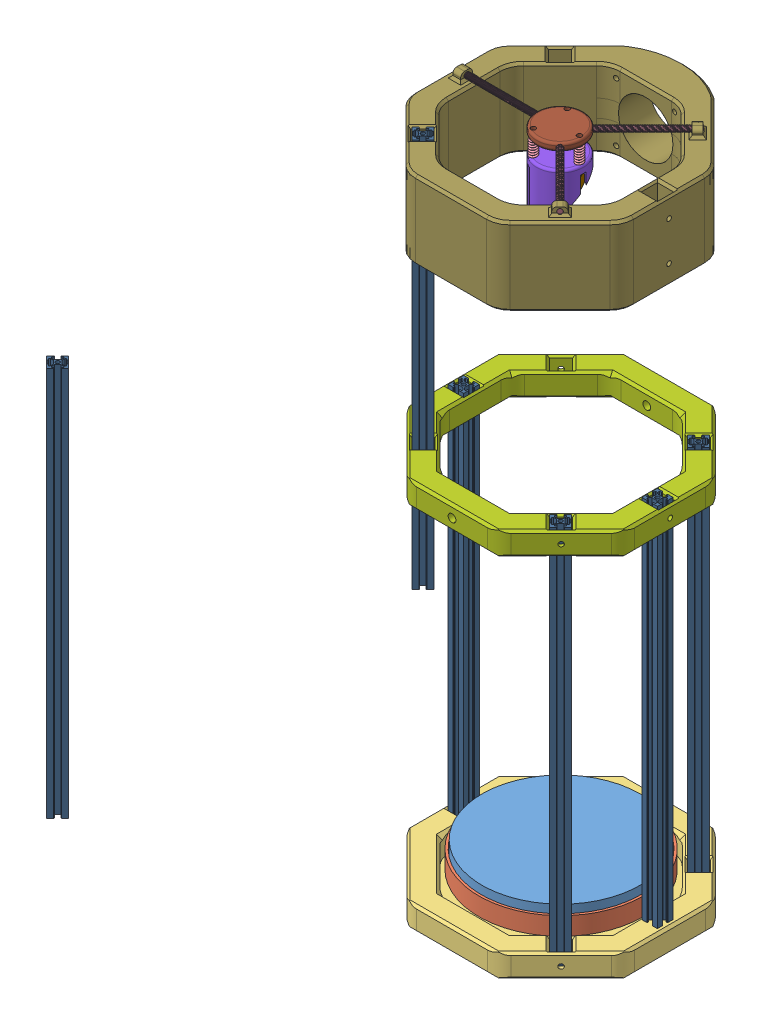
SolidWorks assembly telescope, configuration Default. Lengths in mm.
Overall size (446.79 865.74 529.28).
35 component instances, 13 part files, 75 mates.
Components (placement in the parent):
- primary_mirror-1: primary_mirror [Default] at origin size (203.2 25 203.2)
- primary_mirror_mount-1: primary_mirror_mount [Default] at (0 -5 0) x (0.5 0 -0.866025) z (0.866025 0 0.5) size (211 23 211)
- bottom_ring-1: bottom_ring [Default] at (0 -32 0) x (0 0 -1) z (1 0 0) size (280 30 280)
- spring-4: spring [Default] at (60.6218 -28 -35) size (10.35 22 11.55) (flexible)
  - spring-1: spring [Default] at origin size (10.35 22 11.55)
- spring-5: spring [Default] at (0 -28 70) size (10.35 22 11.55) (flexible)
  - spring-1: spring [Default] at origin size (10.35 22 11.55)
- spring-6: spring [Default] at (-60.6218 -28 -35) size (10.35 22 11.55) (flexible)
  - spring-1: spring [Default] at origin size (10.35 22 11.55)
- hexalobular socket cheese head_iso-8: hexalobular socket cheese head_iso [ISO 14580 - #6 x 40 x 38 - 4.8-N] at (-60.6218 -45 -35) size (10 44.4 10)
- hexalobular socket cheese head_iso-9: hexalobular socket cheese head_iso [ISO 14580 - #6 x 40 x 38 - 4.8-N] at (60.6218 -45 -35) size (10 44.4 10)
- hexalobular socket cheese head_iso-10: hexalobular socket cheese head_iso [ISO 14580 - #6 x 40 x 38 - 4.8-N] at (0 -45 70) size (10 44.4 10)
- hex nut gradec_iso-5: hex nut gradec_iso [ISO - 4034 - M6 - N] at (60.6218 -38.1 -35) x (1 0 0) z (0 -1 0) size (10 11.55 6.1)
- hex nut gradec_iso-6: hex nut gradec_iso [ISO - 4034 - M6 - N] at (-60.6218 -38.1 -35) x (1 0 0) z (0 -1 0) size (10 11.55 6.1)
- hex nut gradec_iso-7: hex nut gradec_iso [ISO - 4034 - M6 - N] at (0 -38.1 70) x (0.980222 0 -0.197901) z (0 -1 0) size (10 11.55 6.1)
- middle_ring-1: middle_ring [Default] at (0 437.3298 0) x (0 0 1) z (-1 0 0) size (280 30 280)
- secondary_mirror_mount-2: secondary_mirror_mount [Default] at (-0.7071 790.2811 0.7071) x (-0.5 0 0.866025) z (0.866025 0 0.5) size (60 72.96 60)
- secondary_mirror-2: secondary_mirror [Default] at (-1.1853 758.4823 0.5609) x (-0.353553 -0.707107 0.612372) z (-0.353553 0.707107 0.612372) size (80.71 50 10)
- spring-12: spring [Default] at (-13.2071 790.2811 22.3577) size (10.35 22 11.55)
  - spring-1: spring [Default] at origin size (10.35 22 11.55)
- spring-13: spring [Default] at (-13.2071 790.2811 -20.9435) size (10.35 22 11.55)
  - spring-1: spring [Default] at origin size (10.35 22 11.55)
- spring-14: spring [Default] at (24.2929 790.2811 0.7071) size (10.35 22 11.55)
  - spring-1: spring [Default] at origin size (10.35 22 11.55)
- aluminum_extrusion-1: aluminum_extrusion [Default] at (88.3883 -32 89.0955) x (0.707107 0 0.707107) z (-0.707107 0 0.707107) size (20 500 20)
- aluminum_extrusion-2: aluminum_extrusion [Default] at (-125.5 -32 -0.5) x (-1 0 0) z (0 0 -1) size (20 500 20)
- aluminum_extrusion-3: aluminum_extrusion [Default] at (88.3883 -32 -87.6812) x (-0.707107 0 0.707107) z (-0.707107 0 -0.707107) size (20 500 20)
- secondary_mirror_mount_2-1: secondary_mirror_mount_2 [Default] at (-0.7071 810.2811 0.7071) x (0 0 1) z (-1 0 0) size (60 10.36 60.12)
- upper_ring_focuser-2: upper_ring_focuser [Default] at (-0.7071 710.2811 0.7071) x (-1 0 0) z (0 0 -1) size (280 110 298.17)
- aluminum_extrusion-4: aluminum_extrusion [Default] at (-88.3883 310.2811 89.0955) x (0.707107 0 0.707107) z (-0.707107 0 0.707107) size (20 500 20)
- Threaded Rod-2: Threaded Rod [90mm, 6mm] at (13.435 815.2811 -13.435) x (0.5 0.707107 0.5) z (0.5 -0.707107 0.5) size (7.18 110.79 8.28)
- Threaded Rod-3: Threaded Rod [90mm, 6mm] at (91.2168 815.2811 92.631) x (-0.706924 0.022716 0.706924) z (0.016062 0.999742 -0.016062) size (7.18 110.79 8.28)
- Threaded Rod-4: Threaded Rod [90mm, 6mm] at (-130.7071 815.2811 0.7071) x (0 -0.381849 0.924225) z (0 -0.924225 -0.381849) size (7.18 110.79 8.28)
- aluminum_extrusion-5: aluminum_extrusion [Default] at (-288.5277 90.2535 357.666) x (0.707107 0 0.707107) z (-0.707107 0 0.707107) size (20 500 20)
- aluminum_extrusion-6: aluminum_extrusion [Default] at (123.7929 467.4029 0.2071) x (-1 0 0) z (0 0 1) size (20 500 20)
Mates (geometry in assembly coordinates):
- Concentric1: concentric aligned: cylinder of primary_mirror-1 through (0 25 0) axis (0 -1 0) radius 101.6; cylinder of primary_mirror_mount-1 through (0 15 0) axis (0 -1 0) radius 102.5
- Coincident2: coordinate: point of primary_mirror-1
- Parallel1: parallel anti-aligned: plane of primary_mirror-1 through (0 25 0) normal (0 1 0); plane of middle_ring-1 through (0 437.3298 0) normal (0 -1 0)
- Coincident4: coincident aligned: line of middle_ring-1 through (0 468.8298 0) axis (0 -1 0)
- Parallel2: parallel anti-aligned: plane of middle_ring-1 through (-140 467.3298 -57.9899) normal (-1 0 0)
- Coincident6: coincident aligned: line of bottom_ring-1 through (33 0 -0.5) axis (0 0 -1)
- Parallel3: parallel anti-aligned: plane of middle_ring-1 through (-57.9899 467.3298 140) normal (0 0 1); plane of bottom_ring-1 through (57.9899 -2 -140) normal (0 0 -1)
- Concentric2: concentric anti-aligned: cylinder of primary_mirror_mount-1 through (-60.6218 0 -35) axis (0 -1 0) radius 6.5; cylinder of bottom_ring-1 through (-60.6218 -32 -35) axis (0 1 0) radius 3
- Concentric6: concentric: cylinder of bottom_ring-1 through (60.6218 -32 -35) axis (0 1 0) radius 3; point of spring-4
- Concentric7: concentric: cylinder of bottom_ring-1 through (0 -32 70) axis (0 1 0) radius 3; point of spring-5
- Concentric8: concentric: cylinder of bottom_ring-1 through (-60.6218 -32 -35) axis (0 1 0) radius 3; point of spring-6
- Coincident24: coincident anti-aligned: plane of bottom_ring-1 through (0 -28 0) normal (0 1 0); plane of spring-5/spring-1 through (0 -28 70) normal (0 -1 0)
- Coincident25: coincident anti-aligned: plane of bottom_ring-1 through (0 -28 0) normal (0 1 0); plane of spring-4/spring-1 through (60.6218 -28 -35) normal (0 -1 0)
- Coincident26: coincident anti-aligned: plane of bottom_ring-1 through (0 -28 0) normal (0 1 0); plane of spring-6/spring-1 through (-60.6218 -28 -35) normal (0 -1 0)
- Parallel6: parallel aligned: plane of spring-4 through (60.6218 -28 -35) normal (0 0 1)
- Parallel7: parallel aligned: plane of spring-5 through (0 -28 70) normal (0 0 1)
- Parallel8: parallel aligned: plane of spring-6 through (-60.6218 -28 -35) normal (0 0 1)
- Coincident32: coincident anti-aligned: plane of primary_mirror_mount-1 through (0 -8 0) normal (0 -1 0); plane of spring-6/spring-1 through (-60.6218 -8 -35) normal (0 1 0)
- Concentric13: concentric aligned: cylinder of primary_mirror_mount-1 through (-60.6218 0 -35) axis (0 -1 0) radius 6.5; cylinder of hexalobular socket cheese head_iso-8 through (-60.6218 -45 -35) axis (0 -1 0) radius 3.4
- Coincident36: coincident anti-aligned: plane of primary_mirror_mount-1 through (0 -5 0) normal (0 1 0); plane of hexalobular socket cheese head_iso-8 through (-57.6218 -5 -35) normal (0 -1 0)
- Concentric14: concentric anti-aligned: cylinder of primary_mirror_mount-1 through (60.6218 -8 -35) axis (0 1 0) radius 3; cylinder of hexalobular socket cheese head_iso-9 through (60.6218 -45 -35) axis (0 -1 0) radius 3.4
- Coincident37: coincident anti-aligned: plane of primary_mirror_mount-1 through (0 -5 0) normal (0 1 0); plane of hexalobular socket cheese head_iso-9 through (63.6218 -5 -35) normal (0 -1 0)
- Concentric15: concentric anti-aligned: cylinder of primary_mirror_mount-1 through (0 -8 70) axis (0 1 0) radius 3; cylinder of hexalobular socket cheese head_iso-10 through (0 -45 70) axis (0 -1 0) radius 3.4
- Coincident38: coincident anti-aligned: plane of primary_mirror_mount-1 through (0 -5 0) normal (0 1 0); plane of hexalobular socket cheese head_iso-10 through (3 -5 70) normal (0 -1 0)
- Coincident40: coincident anti-aligned: plane of primary_mirror-1 through (0 0 0) normal (0 -1 0); plane of primary_mirror_mount-1 through (0 0 0) normal (0 1 0)
- Concentric19: concentric aligned: cylinder of hexalobular socket cheese head_iso-9 through (60.6218 -45 -35) axis (0 -1 0) radius 3.4; cylinder of hex nut gradec_iso-5 through (60.6218 -13.0625 -35) axis (0 -1 0) radius 3
- Coincident41: coincident anti-aligned: plane of bottom_ring-1 through (0 -32 0) normal (0 -1 0); plane of hex nut gradec_iso-5 through (50.6218 -32 -35) normal (0 1 0)
- Concentric20: concentric aligned: cylinder of hexalobular socket cheese head_iso-8 through (-60.6218 -45 -35) axis (0 -1 0) radius 3.4; cylinder of hex nut gradec_iso-6 through (-60.6218 -13.0625 -35) axis (0 -1 0) radius 3
- Coincident42: coincident anti-aligned: plane of bottom_ring-1 through (0 -32 0) normal (0 -1 0); plane of hex nut gradec_iso-6 through (-70.6218 -32 -35) normal (0 1 0)
- Concentric21: concentric aligned: cylinder of hexalobular socket cheese head_iso-10 through (0 -45 70) axis (0 -1 0) radius 3.4; cylinder of hex nut gradec_iso-7 through (0 -13.0625 70) axis (0 -1 0) radius 3
- Coincident43: coincident anti-aligned: plane of bottom_ring-1 through (0 -32 0) normal (0 -1 0); plane of hex nut gradec_iso-7 through (-9.8022 -32 71.979) normal (0 1 0)
- Coincident45: coincident anti-aligned: plane of secondary_mirror_mount-2 through (7.2145 774.4379 -13.0135) normal (0.353553 -0.707107 -0.612372); plane of secondary_mirror-2 through (-1.1853 758.4823 0.5609) normal (-0.353553 0.707107 0.612372)
- Parallel12: parallel: cylinder of assembly; face of secondary_mirror_mount-2; cylinder of secondary_mirror-2 through (-1.1853 793.8377 0.5609) axis (0 -1 0) radius 25
- Parallel13: parallel: cylinder of assembly; face of secondary_mirror_mount-2; cylinder of secondary_mirror-2 through (-1.1853 793.8377 0.5609) axis (0 -1 0) radius 25
- Tangent3: tangent: cylinder of assembly; face of secondary_mirror_mount-2; cylinder of secondary_mirror-2 through (-1.1853 793.8377 0.5609) axis (0 -1 0) radius 25
- Parallel15: parallel aligned: plane of secondary_mirror_mount-2 through (-0.7071 790.2811 0.7071) normal (0 1 0)
- Coincident51: coincident anti-aligned: plane of secondary_mirror_mount-2 through (-0.7071 790.2811 0.7071) normal (0 1 0); plane of spring-12/spring-1 through (-13.2071 790.2811 22.3577) normal (0 -1 0)
- Concentric22: concentric: cylinder of secondary_mirror_mount-2 through (-13.2071 790.2811 22.3577) axis (0 -1 0) radius 3; point of spring-12
- Coincident53: coincident anti-aligned: plane of secondary_mirror_mount-2 through (-0.7071 790.2811 0.7071) normal (0 1 0); plane of spring-13/spring-1 through (-13.2071 790.2811 -20.9435) normal (0 -1 0)
- Concentric23: concentric: cylinder of secondary_mirror_mount-2 through (-13.2071 790.2811 -20.9435) axis (0 -1 0) radius 3; point of spring-13
- Coincident55: coincident anti-aligned: plane of secondary_mirror_mount-2 through (-0.7071 790.2811 0.7071) normal (0 1 0); plane of spring-14/spring-1 through (24.2929 790.2811 0.7071) normal (0 -1 0)
- Concentric24: concentric: cylinder of secondary_mirror_mount-2 through (24.2929 790.2811 0.7071) axis (0 -1 0) radius 3; point of spring-14
- LimitDistance1: limit distance = 733.4823 mm: plane of primary_mirror-1 through (0 25 0) normal (0 1 0); point of secondary_mirror-2
- Coincident62: coincident aligned: plane of bottom_ring-1 through (0 -32 0) normal (0 -1 0); plane of aluminum_extrusion-1 through (88.3883 -32 89.0955) normal (0 -1 0)
- Coincident63: coincident anti-aligned: plane of bottom_ring-1 through (88.3883 -2 103.2376) normal (0.707107 0 -0.707107); plane of aluminum_extrusion-1 through (81.3173 468 96.1665) normal (-0.707107 0 0.707107)
- Coincident65: coincident anti-aligned: plane of bottom_ring-1 through (103.2376 -2 88.3883) normal (-0.707107 0 -0.707107); plane of aluminum_extrusion-1 through (95.4594 468 96.1665) normal (0.707107 0 0.707107)
- Coincident66: coincident aligned: plane of bottom_ring-1 through (0 -32 0) normal (0 -1 0); plane of aluminum_extrusion-3 through (88.3883 -32 -87.6812) normal (0 -1 0)
- Coincident67: coincident aligned: plane of bottom_ring-1 through (0 -32 0) normal (0 -1 0); plane of aluminum_extrusion-2 through (-125.5 -32 -0.5) normal (0 -1 0)
- Coincident68: coincident anti-aligned: plane of bottom_ring-1 through (-135.5 -2 10.5) normal (1 0 0); plane of aluminum_extrusion-2 through (-135.5 468 -0.5) normal (-1 0 0)
- Coincident69: coincident anti-aligned: plane of bottom_ring-1 through (-135.5 -2 -10.5) normal (0 0 1); plane of aluminum_extrusion-2 through (-125.5 468 -10.5) normal (0 0 -1)
- Coincident70: coincident anti-aligned: plane of bottom_ring-1 through (73.5391 -2 -88.3883) normal (0.707107 0 -0.707107); plane of aluminum_extrusion-3 through (81.3173 468 -80.6102) normal (-0.707107 0 0.707107)
- Coincident71: coincident anti-aligned: plane of bottom_ring-1 through (103.2376 -2 -88.3883) normal (-0.707107 0 -0.707107); plane of aluminum_extrusion-3 through (95.4594 468 -80.6102) normal (0.707107 0 0.707107)
- Coincident72: coincident anti-aligned: plane of spring-12/spring-1 through (-13.2071 810.2811 22.3577) normal (0 1 0); plane of secondary_mirror_mount_2-1 through (-0.7071 810.2811 0.7071) normal (0 -1 0)
- Concentric25: concentric: point of spring-14; cylinder of secondary_mirror_mount_2-1 through (24.2929 820.2811 0.7071) axis (0 -1 0) radius 3
- Concentric26: concentric: point of spring-13; cylinder of secondary_mirror_mount_2-1 through (-13.2071 820.2811 -20.9435) axis (0 -1 0) radius 3
- LimitDistance2: limit distance = 0.6702 mm aligned: plane of middle_ring-1 through (0 467.3298 0) normal (0 1 0); plane of aluminum_extrusion-1 through (88.3883 468 89.0955) normal (0 1 0)
- Coincident78: coincident anti-aligned: plane of middle_ring-1 through (-88.3883 467.3298 103.2376) normal (0.707107 0 -0.707107); plane of aluminum_extrusion-4 through (-95.4594 810.2811 96.1665) normal (-0.707107 0 0.707107)
- Coincident79: coincident anti-aligned: plane of middle_ring-1 through (-88.3883 467.3298 103.2376) normal (-0.707107 0 -0.707107); plane of aluminum_extrusion-4 through (-81.3173 810.2811 96.1665) normal (0.707107 0 0.707107)
- LimitDistance4: limit distance = 127.0487 mm aligned: plane of middle_ring-1 through (0 437.3298 0) normal (0 -1 0); plane of aluminum_extrusion-4 through (-88.3883 310.2811 89.0955) normal (0 -1 0)
- Concentric27: concentric aligned: cylinder of secondary_mirror_mount_2-1 through (-30.7071 815.2811 0.7071) axis (1 0 0) radius 3; cylinder of upper_ring_focuser-2 through (-130.7071 815.2811 0.7071) axis (1 0 0) radius 3
- Parallel16: parallel aligned: plane of middle_ring-1 through (0 467.3298 0) normal (0 1 0); plane of aluminum_extrusion-1 through (88.3883 468 89.0955) normal (0 1 0)
- Concentric28: concentric aligned: cylinder of secondary_mirror_mount_2-1 through (29.2929 815.2811 -29.2929) axis (-0.707107 0 0.707107) radius 3; cylinder of upper_ring_focuser-2 through (91.2168 815.2811 -91.2168) axis (-0.707107 0 0.707107) radius 3
- Coincident85: coincident anti-aligned: plane of upper_ring_focuser-2 through (6.7175 810.2811 8.1317) normal (-0.707107 0 -0.707107); plane of aluminum_extrusion-4 through (-81.3173 810.2811 96.1665) normal (0.707107 0 0.707107)
- Coincident86: coincident anti-aligned: plane of upper_ring_focuser-2 through (-81.6708 810.2811 81.6708) normal (-0.707107 0 0.707107); plane of aluminum_extrusion-4 through (-81.3173 810.2811 82.0244) normal (0.707107 0 -0.707107)
- LimitDistance5: limit distance = 332.2811 mm anti-aligned: plane of aluminum_extrusion-2 through (-125.5 468 -0.5) normal (0 1 0); plane of upper_ring_focuser-2 through (-0.7071 800.2811 0.7071) normal (0 -1 0)
- Coincident88: coincident aligned: plane of upper_ring_focuser-2 through (-0.7071 810.2811 0.7071) normal (0 1 0); plane of aluminum_extrusion-4 through (-88.3883 810.2811 89.0955) normal (0 1 0)
- Concentric29: concentric anti-aligned: cylinder of secondary_mirror_mount_2-1 through (29.2929 815.2811 -29.2929) axis (-0.707107 0 0.707107) radius 3; circle of Threaded Rod-2
- Coincident91: coincident aligned: plane of upper_ring_focuser-2 through (92.9845 815.2811 -89.449) normal (0.707107 0 -0.707107); plane of Threaded Rod-2 through (91.2168 815.2811 -91.2168) normal (0.707107 0 -0.707107)
- Coincident92: coincident aligned: plane of upper_ring_focuser-2 through (89.449 815.2811 94.3988) normal (0.707107 0 0.707107); plane of Threaded Rod-3 through (91.2168 815.2811 92.631) normal (0.707107 0 0.707107)
- Concentric30: concentric aligned: cylinder of secondary_mirror_mount_2-1 through (29.2929 815.2811 30.7071) axis (-0.707107 0 -0.707107) radius 3; circle of Threaded Rod-3
- Coincident93: coincident aligned: plane of upper_ring_focuser-2 through (-130.7071 815.2811 -1.7929) normal (-1 0 0); plane of Threaded Rod-4 through (-130.7071 815.2811 0.7071) normal (-1 0 0)
- Concentric31: concentric aligned: cylinder of secondary_mirror_mount_2-1 through (-30.7071 815.2811 0.7071) axis (1 0 0) radius 3; circle of Threaded Rod-4
- Coincident95: coincident anti-aligned: plane of upper_ring_focuser-2 through (113.7929 810.2811 0.7071) normal (1 0 0); plane of aluminum_extrusion-6 through (113.7929 -32.5971 0.2071) normal (-1 0 0)
- Coincident96: coincident anti-aligned: plane of upper_ring_focuser-2 through (-0.7071 810.2811 -9.7929) normal (0 0 1); plane of aluminum_extrusion-6 through (123.7929 -32.5971 -9.7929) normal (0 0 -1)
- LimitDistance6: limit distance = 0.0732 mm aligned: plane of middle_ring-1 through (0 467.3298 0) normal (0 1 0); plane of aluminum_extrusion-6 through (123.7929 467.4029 0.2071) normal (0 1 0)
